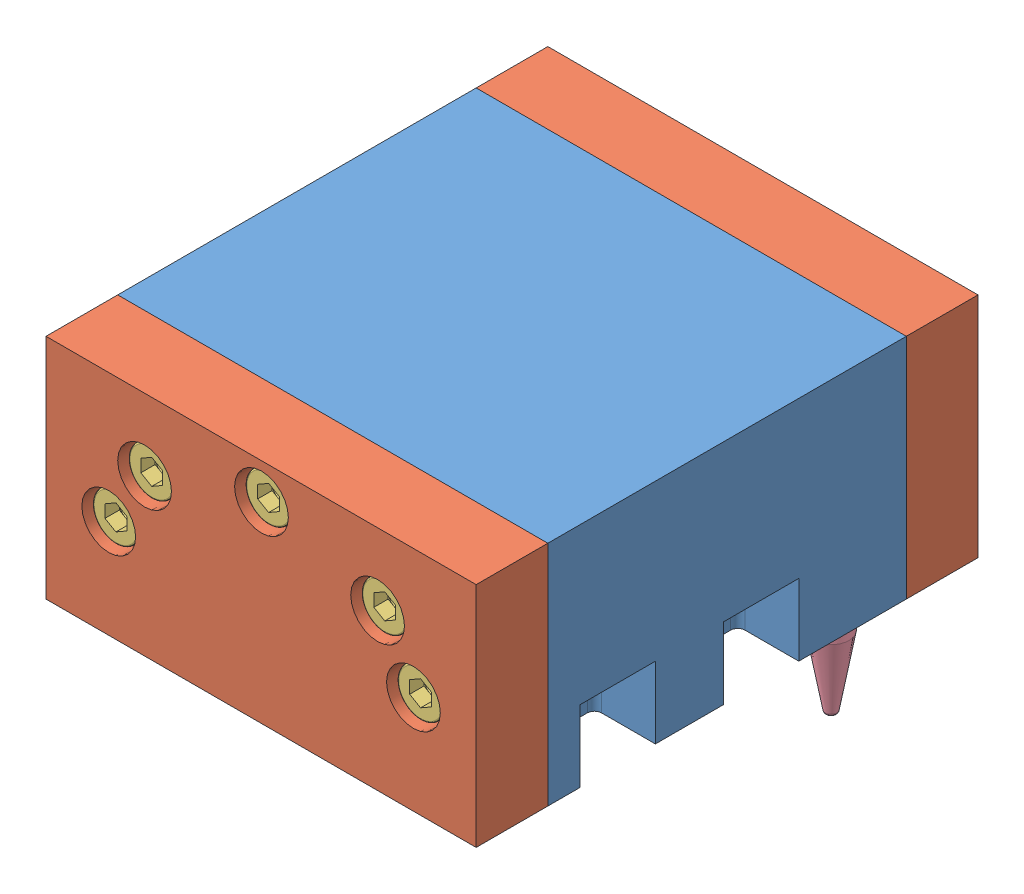
SolidWorks assembly СборкаНиз, configuration По умолчанию. Lengths in mm.
Overall size (120 88.5 140).
17 component instances, 5 part files, 34 mates.
Components (placement in the parent):
- Матрица-1: Матрица [По умолчанию] at origin size (120 63.5 100)
- БоковинаПресс-формы-1: БоковинаПресс-формы [По умолчанию] at (0 63.5 0) x (0 0 -1) z (-1 0 0) size (20 63.5 120)
- БоковинаПресс-формы-2: БоковинаПресс-формы [По умолчанию] at (120 63.5 100) x (0 0 1) z (1 0 0) size (20 63.5 120)
- socket head cap screw_iso-1: socket head cap screw_iso [ISO 4762 M8 x 16 - 16N] at (17.5 27.5 118) x (0 0 -1) z (1 0 0) size (24 13 13)
- socket head cap screw_iso-2: socket head cap screw_iso [ISO 4762 M8 x 16 - 16N] at (27.5 43.5 118) x (0 0 -1) z (1 0 0) size (24 13 13)
- socket head cap screw_iso-3: socket head cap screw_iso [ISO 4762 M8 x 16 - 16N] at (60.109 53.5 118) x (0 0 -1) z (1 0 0) size (24 13 13)
- socket head cap screw_iso-4: socket head cap screw_iso [ISO 4762 M8 x 16 - 16N] at (92.5 43.5 118) x (0 0 -1) z (1 0 0) size (24 13 13)
- socket head cap screw_iso-5: socket head cap screw_iso [ISO 4762 M8 x 16 - 16N] at (102.5 27.5 118) x (0 0 -1) z (1 0 0) size (24 13 13)
- socket head cap screw_iso-6: socket head cap screw_iso [ISO 4762 M8 x 16 - 16N] at (102.5 27.5 -18) x (0 0 1) z (-1 0 0) size (24 13 13)
- socket head cap screw_iso-7: socket head cap screw_iso [ISO 4762 M8 x 16 - 16N] at (92.5 43.5 -18) x (0 0 1) z (-1 0 0) size (24 13 13)
- socket head cap screw_iso-8: socket head cap screw_iso [ISO 4762 M8 x 16 - 16N] at (59.891 53.5 -18) x (0 0 1) z (-1 0 0) size (24 13 13)
- socket head cap screw_iso-9: socket head cap screw_iso [ISO 4762 M8 x 16 - 16N] at (27.5 43.5 -18) x (0 0 1) z (-1 0 0) size (24 13 13)
- socket head cap screw_iso-10: socket head cap screw_iso [ISO 4762 M8 x 16 - 16N] at (17.5 27.5 -18) x (0 0 1) z (-1 0 0) size (24 13 13)
- Направляющая-2: Направляющая [По умолчанию] at (8 30 88) x (0 -1 0) z (0.779572 0 -0.626312) size (55 10 10)
- Направляющая-3: Направляющая [По умолчанию] at (112 30 13) x (0 -1 0) z (-0.854743 0 -0.519052) size (55 10 10)
- Подставка-1: Подставка [По умолчанию] at (60 33.5 77) x (0 -1 0) z (-0.902288 0 0.431134) size (36.5 13.89 13.89)
- Подставка-2: Подставка [По умолчанию] at (60 33.5 23) x (0 -1 0) z (-0.706159 0 0.708053) size (36.5 13.89 13.89)
Mates (geometry in assembly coordinates):
- Совпадение1: coincident anti-aligned: plane of Матрица-1 through (0 0 0) normal (0 0 -1); plane of БоковинаПресс-формы-1 through (0 63.5 0) normal (0 0 1)
- Концентричный1: concentric aligned: cylinder of Матрица-1 through (92.5 43.5 30) axis (0 0 -1) radius 4; cylinder of БоковинаПресс-формы-1 through (92.5 43.5 0) axis (0 0 -1) radius 4.25
- Концентричный2: concentric aligned: cylinder of Матрица-1 through (27.5 43.5 30) axis (0 0 -1) radius 4; cylinder of БоковинаПресс-формы-1 through (27.5 43.5 0) axis (0 0 -1) radius 4.25
- Совпадение2: coincident anti-aligned: plane of Матрица-1 through (0 0 100) normal (0 0 1); plane of БоковинаПресс-формы-2 through (120 63.5 100) normal (0 0 -1)
- Концентричный4: concentric aligned: cylinder of Матрица-1 through (17.5 27.5 70) axis (0 0 1) radius 4; cylinder of БоковинаПресс-формы-2 through (17.5 27.5 100) axis (0 0 1) radius 4.25
- Концентричный5: concentric aligned: cylinder of Матрица-1 through (102.5 27.5 70) axis (0 0 1) radius 4; cylinder of БоковинаПресс-формы-2 through (102.5 27.5 100) axis (0 0 1) radius 4.25
- Концентричный6: concentric aligned: cylinder of БоковинаПресс-формы-2 through (17.5 27.5 100) axis (0 0 1) radius 4.25; cylinder of socket head cap screw_iso-1 through (17.5 27.5 149.75) axis (0 0 1) radius 6.5
- Совпадение3: coincident anti-aligned: plane of БоковинаПресс-формы-2 through (17.5 27.5 110) normal (0 0 1); plane of socket head cap screw_iso-1 through (17.5 34 110) normal (0 0 -1)
- Концентричный7: concentric aligned: cylinder of БоковинаПресс-формы-2 through (27.5 43.5 110) axis (0 0 1) radius 7.5; cylinder of socket head cap screw_iso-2 through (27.5 43.5 149.75) axis (0 0 1) radius 6.5
- Совпадение4: coincident anti-aligned: plane of БоковинаПресс-формы-2 through (27.5 43.5 110) normal (0 0 1); plane of socket head cap screw_iso-2 through (27.5 50 110) normal (0 0 -1)
- Концентричный8: concentric aligned: cylinder of БоковинаПресс-формы-2 through (60.109 53.5 100) axis (0 0 1) radius 4.25; cylinder of socket head cap screw_iso-3 through (60.109 53.5 149.75) axis (0 0 1) radius 6.5
- Совпадение5: coincident anti-aligned: plane of БоковинаПресс-формы-2 through (60.109 53.5 110) normal (0 0 1); plane of socket head cap screw_iso-3 through (60.109 60 110) normal (0 0 -1)
- Концентричный9: concentric aligned: cylinder of БоковинаПресс-формы-2 through (92.5 43.5 100) axis (0 0 1) radius 4.25; cylinder of socket head cap screw_iso-4 through (92.5 43.5 149.75) axis (0 0 1) radius 6.5
- Совпадение6: coincident anti-aligned: plane of БоковинаПресс-формы-2 through (92.5 43.5 110) normal (0 0 1); plane of socket head cap screw_iso-4 through (92.5 50 110) normal (0 0 -1)
- Концентричный10: concentric aligned: cylinder of БоковинаПресс-формы-2 through (102.5 27.5 100) axis (0 0 1) radius 4.25; cylinder of socket head cap screw_iso-5 through (102.5 27.5 149.75) axis (0 0 1) radius 6.5
- Совпадение7: coincident anti-aligned: plane of БоковинаПресс-формы-2 through (102.5 27.5 110) normal (0 0 1); plane of socket head cap screw_iso-5 through (102.5 34 110) normal (0 0 -1)
- Концентричный11: concentric aligned: cylinder of БоковинаПресс-формы-1 through (102.5 27.5 0) axis (0 0 -1) radius 4.25; cylinder of socket head cap screw_iso-6 through (102.5 27.5 -49.75) axis (0 0 -1) radius 6.5
- Совпадение8: coincident anti-aligned: plane of БоковинаПресс-формы-1 through (102.5 27.5 -10) normal (0 0 -1); plane of socket head cap screw_iso-6 through (102.5 34 -10) normal (0 0 1)
- Концентричный12: concentric aligned: cylinder of БоковинаПресс-формы-1 through (92.5 43.5 -10) axis (0 0 -1) radius 7.5; cylinder of socket head cap screw_iso-7 through (92.5 43.5 -49.75) axis (0 0 -1) radius 6.5
- Совпадение9: coincident anti-aligned: plane of БоковинаПресс-формы-1 through (92.5 43.5 -10) normal (0 0 -1); plane of socket head cap screw_iso-7 through (92.5 50 -10) normal (0 0 1)
- Концентричный13: concentric aligned: cylinder of БоковинаПресс-формы-1 through (59.891 53.5 0) axis (0 0 -1) radius 4.25; cylinder of socket head cap screw_iso-8 through (59.891 53.5 -49.75) axis (0 0 -1) radius 6.5
- Совпадение10: coincident anti-aligned: plane of БоковинаПресс-формы-1 through (59.891 53.5 -10) normal (0 0 -1); plane of socket head cap screw_iso-8 through (59.891 60 -10) normal (0 0 1)
- Концентричный14: concentric aligned: cylinder of БоковинаПресс-формы-1 through (27.5 43.5 0) axis (0 0 -1) radius 4.25; cylinder of socket head cap screw_iso-9 through (27.5 43.5 -49.75) axis (0 0 -1) radius 6.5
- Совпадение11: coincident anti-aligned: plane of БоковинаПресс-формы-1 through (27.5 43.5 -10) normal (0 0 -1); plane of socket head cap screw_iso-9 through (27.5 50 -10) normal (0 0 1)
- Концентричный15: concentric aligned: cylinder of БоковинаПресс-формы-1 through (17.5 27.5 -10) axis (0 0 -1) radius 7.5; cylinder of socket head cap screw_iso-10 through (17.5 27.5 -49.75) axis (0 0 -1) radius 6.5
- Совпадение12: coincident anti-aligned: plane of БоковинаПресс-формы-1 through (17.5 27.5 -10) normal (0 0 -1); plane of socket head cap screw_iso-10 through (17.5 34 -10) normal (0 0 1)
- Концентричный18: concentric anti-aligned: cylinder of Матрица-1 through (8 30 88) axis (0 -1 0) radius 5; cylinder of Направляющая-2 through (8 30 88) axis (0 1 0) radius 5
- Совпадение13: coincident anti-aligned: plane of Матрица-1 through (8 30 88) normal (0 -1 0); plane of Направляющая-2 through (8 30 88) normal (0 1 0)
- Концентричный19: concentric anti-aligned: cylinder of Матрица-1 through (112 30 13) axis (0 -1 0) radius 5; cylinder of Направляющая-3 through (112 30 13) axis (0 1 0) radius 5
- Совпадение14: coincident anti-aligned: plane of Матрица-1 through (112 30 13) normal (0 -1 0); plane of Направляющая-3 through (112 30 13) normal (0 1 0)
- Концентричный20: concentric anti-aligned: cylinder of Матрица-1 through (60 33.5 77) axis (0 -1 0) radius 6; cylinder of Подставка-1 through (60 33.5 77) axis (0 1 0) radius 6.9453
- Концентричный21: concentric anti-aligned: cylinder of Матрица-1 through (60 33.5 23) axis (0 -1 0) radius 6; cylinder of Подставка-2 through (60 33.5 23) axis (0 1 0) radius 6.9453
- Совпадение16: coincident anti-aligned: plane of Матрица-1 through (60 33.5 23) normal (0 -1 0); plane of Подставка-2 through (60 33.5 23) normal (0 1 0)
- Совпадение18: coincident aligned: plane of Подставка-1 through (63.6092 -3 75.2755) normal (0 -1 0); plane of Подставка-2 through (62.8246 -3 20.1678) normal (0 -1 0)
